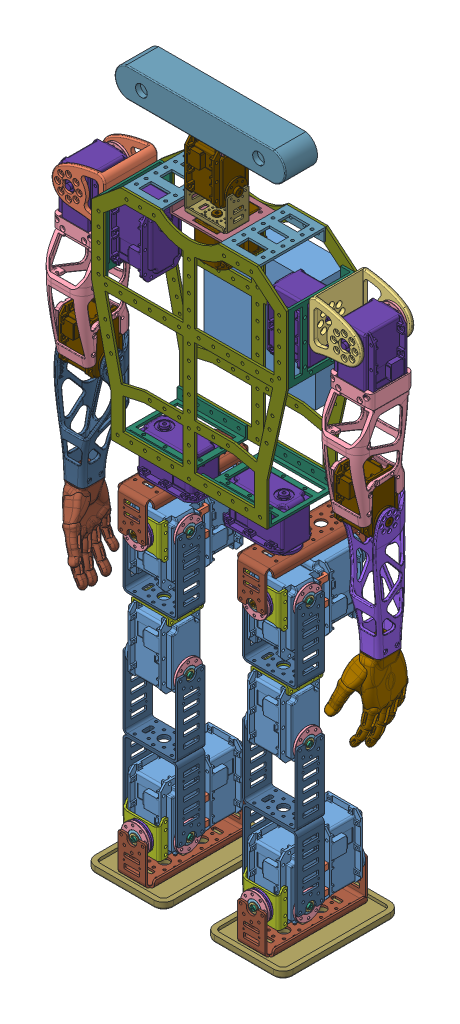
SolidWorks assembly main, configuration Default. Lengths in mm.
Overall size (334.21 729.22 145.63).
144 component instances, 32 part files, 59 mates.
Components (placement in the parent):
- leg_l2-1: leg_l2 [Default] at (32.287 -223.4121 -197.7719) x (0 0 1) z (-1 0 0) size (106.88 70.06 58.88)
  - MX-106T_step-1: MX-106T_step [Default] at origin size (40.2 65.92 55.3)
  - MX-106T_step-2: MX-106T_step [Default] at (-44 0 0) x (0 0 1) z (-1 0 0) size (40.2 65.92 55.3)
  - FR08-X101_2017-1: FR08-X101_2017 [Default] at (-27 -7 -17) x (0 -1 0) z (0 0 1) size (28 12.3 4.8)
  - FR08-X101_2017-2: FR08-X101_2017 [Default] at (-27 -7 17) x (0 1 0) z (0 0 -1) size (28 12.3 4.8)
  - RX64-CAP_2017-1: RX64-CAP_2017 [Default] at (0 0 -25.78) x (0.56381 0.825904 0) z (0 0 -1) size (9.5 9.5 2.2)
  - HN05-I101_2017-1: HN05-I101_2017 [Default] at (0 0 -26.02) x (0.824833 -0.565376 0) z (0.565376 0.824833 0) size (28 3.77 28)
  - MF128ZZ_2017-1: MF128ZZ_2017 [Default] at (0 0 -22.3) x (-0.923728 -0.383049 0) z (0.383049 -0.923728 0) size (14 3.48 14)
  - WB_M2.5X8_2017-1: WB_M2.5X8_2017 [Default] at (0 0 -28.08) x (0 0 1) z (0.825904 -0.56381 0) size (5.5 4.5 4.5)
  - FR05-S101_2017-1: FR05-S101_2017 [Default] at (24 0 0) x (0 1 0) z (0 0 1) size (36 9.31 38.02)
  - FR05-F101_2017-1: FR05-F101_2017 [Default] at (24 0 0) x (0 -0.707107 0.707107) z (1 0 0) size (27 27 5)
  - MF128ZZ_2017-2: MF128ZZ_2017 [Default] at (26.3 0 0) x (0 -1 0) z (0 0 1) size (14 3.48 14)
  - WB_M2.5X8_step-1: WB_M2.5X8_step [Default] at (32.08 0 0) x (-1 0 0) z (0 0.546944 0.837169) size (10.5 4.5 4.5)
  - HN05-I101_2017-2: HN05-I101_2017 [Default] at (30.02 0 0) x (0 -1 0) z (0 0 1) size (28 3.77 28)
  - RX64-CAP_2017-2: RX64-CAP_2017 [Default] at (29.78 0 0) x (0 0.837169 -0.546944) z (1 0 0) size (9.5 9.5 2.2)
- leg_l3-2: leg_l3 [Default] at (9.4719 -309.3189 -145.539) x (1 0 0) z (0 1 0) size (58.88 41.6 149.21)
  - HW-64106HXL_2017-1: HW-64106HXL_2017 [Default] at (-3.1848 38.233 13.9067) size (56 28 75)
  - FR05-S101_2017-1: FR05-S101_2017 [Default] at (22.8152 52.233 13.9067) x (0 -1 0) z (1 0 0) size (36 9.31 38.02)
  - MX-106T_step-1: MX-106T_step [Default] at (22.8152 52.233 -40.5933) x (0 1 0) z (-1 0 0) size (40.2 65.92 55.3)
  - HN05-I101_2017-1: HN05-I101_2017 [Default] at (48.8352 52.233 -40.5933) x (0 -0.637924 -0.7701) z (0 -0.7701 0.637924) size (28 3.77 28)
  - RX64-CAP_2017-1: RX64-CAP_2017 [Default] at (48.5952 52.233 -40.5933) x (0 0.837169 -0.546944) z (1 0 0) size (9.5 9.5 2.2)
  - MF128ZZ_2017-1: MF128ZZ_2017 [Default] at (45.1152 52.233 -40.5933) x (0 -0.162836 -0.986653) z (0 -0.986653 0.162836) size (14 3.48 14)
  - WB_M2.5X8_2017-1: WB_M2.5X8_2017 [Default] at (50.8952 52.233 -40.5933) x (-1 0 0) z (0 0.546944 0.837169) size (5.5 4.5 4.5)
- leg_l4-1: leg_l4 [Default] at (-9.8792 -490.5806 -151.7825) x (1 0 0) z (0 1 0) size (56 28 150)
  - HW-64106HXL_2017-1: HW-64106HXL_2017 [Default] at (16.1663 31.9894 68.6685) size (56 28 75)
  - HW-64106HXL_2017-2: HW-64106HXL_2017 [Default] at (68.1663 31.9894 68.6685) x (-1 0 0) z (0 0 -1) size (56 28 75)
- leg_l5-1: leg_l5 [Default] at (76.8682 -440.5941 -231.6442) x (0.699193 -0.033567 0.714144) z (-0.673395 -0.366444 0.642073) size (104.02 99.97 119.36)
  - MX-106T_step-1: MX-106T_step [Default] at (-5.1915 -29.4269 71.3073) x (-0.714144 -0.278818 -0.642073) z (-0.699193 0.240141 0.673395) size (40.2 65.92 55.3)
  - MX-106T_step-2: MX-106T_step [Default] at (-36.6138 -41.6949 43.056) x (0.699193 -0.240141 -0.673395) z (-0.714144 -0.278818 -0.642073) size (40.2 65.92 55.3)
  - FR08-X101_2017-1: FR08-X101_2017 [Default] at (-36.5946 -26.3638 62.8539) x (-0.033567 0.929835 -0.366444) z (0.699193 -0.240141 -0.673395) size (28 12.3 4.8)
  - FR08-X101_2017-2: FR08-X101_2017 [Default] at (-12.8221 -34.5286 39.9585) x (0.033567 -0.929835 0.366444) z (-0.699193 0.240141 0.673395) size (28 12.3 4.8)
  - HN05-I101_2017-1: HN05-I101_2017 [Default] at (13.0015 -35.6754 53.7855) x (0.048348 -0.923861 0.379661) z (0.713296 0.298014 0.634347) size (28 3.77 28)
  - RX64-CAP_2017-1: RX64-CAP_2017 [Default] at (12.8337 -35.6178 53.9472) x (-0.430608 0.610431 -0.664793) z (0.699193 -0.240141 -0.673395) size (9.5 9.5 2.2)
  - HN05-I101_2017-2: HN05-I101_2017 [Default] at (16.2471 -21.0568 90.5823) x (0.601193 -0.714144 -0.35856) z (-0.35856 -0.642073 0.677626) size (28 3.77 28)
  - RX64-CAP_2017-2: RX64-CAP_2017 [Default] at (16.0757 -21.1237 90.4282) x (-0.307188 0.949038 -0.070448) z (0.714144 0.278818 0.642073) size (9.5 9.5 2.2)
  - MF128ZZ_2017-1: MF128ZZ_2017 [Default] at (10.4005 -34.7821 56.2906) x (0.048348 -0.923861 0.379661) z (0.713296 0.298014 0.634347) size (14 3.48 14)
  - WB_M2.5X8_2017-1: WB_M2.5X8_2017 [Default] at (14.4419 -36.1701 52.3983) x (-0.699193 0.240141 0.673395) z (0.570706 0.754788 0.323403) size (5.5 4.5 4.5)
  - MF128ZZ_2017-2: MF128ZZ_2017 [Default] at (13.5905 -22.094 88.1938) x (0.601193 -0.714144 -0.35856) z (-0.35856 -0.642073 0.677626) size (14 3.48 14)
  - WB_M2.5X8_2017-2: WB_M2.5X8_2017 [Default] at (17.7183 -20.4824 91.905) x (-0.714144 -0.278818 -0.642073) z (-0.628994 -0.146927 0.763399) size (5.5 4.5 4.5)
  - FR05-S101_2017-1: FR05-S101_2017 [Default] at (11.948 -22.7353 86.717) x (0.033567 -0.929835 0.366444) z (0.699193 -0.240141 -0.673395) size (36 9.31 38.02)
  - FR05-F101_2017-1: FR05-F101_2017 [Default] at (11.948 -22.7353 86.717) x (0.699193 -0.240141 -0.673395) z (0.714144 0.278818 0.642073) size (27 27 5)
- leg_l6-1: leg_l6 [Default] at (81.6957 -592.3515 -172.7411) x (0 0 -1) z (0 1 0) size (120 80 44)
  - HW-64106HXW_2017-1: HW-64106HXW_2017 [Default] at (-3.9692 33.4087 61.4394) size (105 37.08 40)
  - foot_2017-1: foot_2017 [Default] at (44.5308 49.4087 57.4394) x (-1 0 0) z (0 1 0) size (120 7 80)
- HW-64106HXW_2017-3: HW-64106HXW_2017 [Default] at (170.787 -186.4121 -265.7719) x (0 0 1) z (0 -1 0) size (105 37.08 40)
- leg_l2-2: leg_l2 [Default] at (154.787 -223.4121 -197.7719) x (0 0 1) z (-1 0 0) size (106.88 70.06 58.88)
  - MX-106T_step-1: MX-106T_step [Default] at origin size (40.2 65.92 55.3)
  - MX-106T_step-2: MX-106T_step [Default] at (-44 0 0) x (0 0 1) z (-1 0 0) size (40.2 65.92 55.3)
  - FR08-X101_2017-1: FR08-X101_2017 [Default] at (-27 -7 -17) x (0 -1 0) z (0 0 1) size (28 12.3 4.8)
  - FR08-X101_2017-2: FR08-X101_2017 [Default] at (-27 -7 17) x (0 1 0) z (0 0 -1) size (28 12.3 4.8)
  - RX64-CAP_2017-1: RX64-CAP_2017 [Default] at (0 0 -25.78) x (0.56381 0.825904 0) z (0 0 -1) size (9.5 9.5 2.2)
  - HN05-I101_2017-1: HN05-I101_2017 [Default] at (0 0 -26.02) x (0.824833 -0.565376 0) z (0.565376 0.824833 0) size (28 3.77 28)
  - MF128ZZ_2017-1: MF128ZZ_2017 [Default] at (0 0 -22.3) x (-0.923728 -0.383049 0) z (0.383049 -0.923728 0) size (14 3.48 14)
  - WB_M2.5X8_2017-1: WB_M2.5X8_2017 [Default] at (0 0 -28.08) x (0 0 1) z (0.825904 -0.56381 0) size (5.5 4.5 4.5)
  - FR05-S101_2017-1: FR05-S101_2017 [Default] at (24 0 0) x (0 1 0) z (0 0 1) size (36 9.31 38.02)
  - FR05-F101_2017-1: FR05-F101_2017 [Default] at (24 0 0) x (0 -0.707107 0.707107) z (1 0 0) size (27 27 5)
  - MF128ZZ_2017-2: MF128ZZ_2017 [Default] at (26.3 0 0) x (0 -1 0) z (0 0 1) size (14 3.48 14)
  - WB_M2.5X8_step-1: WB_M2.5X8_step [Default] at (32.08 0 0) x (-1 0 0) z (0 0.546944 0.837169) size (10.5 4.5 4.5)
  - HN05-I101_2017-2: HN05-I101_2017 [Default] at (30.02 0 0) x (0 -1 0) z (0 0 1) size (28 3.77 28)
  - RX64-CAP_2017-2: RX64-CAP_2017 [Default] at (29.78 0 0) x (0 0.837169 -0.546944) z (1 0 0) size (9.5 9.5 2.2)
- leg_l3-3: leg_l3 [Default] at (131.9719 -309.3189 -145.539) x (1 0 0) z (0 1 0) size (58.88 41.6 149.21)
  - HW-64106HXL_2017-1: HW-64106HXL_2017 [Default] at (-3.1848 38.233 13.9067) size (56 28 75)
  - FR05-S101_2017-1: FR05-S101_2017 [Default] at (22.8152 52.233 13.9067) x (0 -1 0) z (1 0 0) size (36 9.31 38.02)
  - MX-106T_step-1: MX-106T_step [Default] at (22.8152 52.233 -40.5933) x (0 1 0) z (-1 0 0) size (40.2 65.92 55.3)
  - HN05-I101_2017-1: HN05-I101_2017 [Default] at (48.8352 52.233 -40.5933) x (0 -0.637924 -0.7701) z (0 -0.7701 0.637924) size (28 3.77 28)
  - RX64-CAP_2017-1: RX64-CAP_2017 [Default] at (48.5952 52.233 -40.5933) x (0 0.837169 -0.546944) z (1 0 0) size (9.5 9.5 2.2)
  - MF128ZZ_2017-1: MF128ZZ_2017 [Default] at (45.1152 52.233 -40.5933) x (0 -0.162836 -0.986653) z (0 -0.986653 0.162836) size (14 3.48 14)
  - WB_M2.5X8_2017-1: WB_M2.5X8_2017 [Default] at (50.8952 52.233 -40.5933) x (-1 0 0) z (0 0.546944 0.837169) size (5.5 4.5 4.5)
- leg_l4-2: leg_l4 [Default] at (112.6208 -490.5806 -151.7825) x (1 0 0) z (0 1 0) size (56 28 150)
  - HW-64106HXL_2017-1: HW-64106HXL_2017 [Default] at (16.1663 31.9894 68.6685) size (56 28 75)
  - HW-64106HXL_2017-2: HW-64106HXL_2017 [Default] at (68.1663 31.9894 68.6685) x (-1 0 0) z (0 0 -1) size (56 28 75)
- leg_l5-2: leg_l5 [Default] at (199.3682 -440.5941 -231.6442) x (0.699193 -0.033567 0.714144) z (-0.673395 -0.366444 0.642073) size (104.02 99.97 119.36)
  - MX-106T_step-1: MX-106T_step [Default] at (-5.1915 -29.4269 71.3073) x (-0.714144 -0.278818 -0.642073) z (-0.699193 0.240141 0.673395) size (40.2 65.92 55.3)
  - MX-106T_step-2: MX-106T_step [Default] at (-36.6138 -41.6949 43.056) x (0.699193 -0.240141 -0.673395) z (-0.714144 -0.278818 -0.642073) size (40.2 65.92 55.3)
  - FR08-X101_2017-1: FR08-X101_2017 [Default] at (-36.5946 -26.3638 62.8539) x (-0.033567 0.929835 -0.366444) z (0.699193 -0.240141 -0.673395) size (28 12.3 4.8)
  - FR08-X101_2017-2: FR08-X101_2017 [Default] at (-12.8221 -34.5286 39.9585) x (0.033567 -0.929835 0.366444) z (-0.699193 0.240141 0.673395) size (28 12.3 4.8)
  - HN05-I101_2017-1: HN05-I101_2017 [Default] at (13.0015 -35.6754 53.7855) x (0.048348 -0.923861 0.379661) z (0.713296 0.298014 0.634347) size (28 3.77 28)
  - RX64-CAP_2017-1: RX64-CAP_2017 [Default] at (12.8337 -35.6178 53.9472) x (-0.430608 0.610431 -0.664793) z (0.699193 -0.240141 -0.673395) size (9.5 9.5 2.2)
  - HN05-I101_2017-2: HN05-I101_2017 [Default] at (16.2471 -21.0568 90.5823) x (0.601193 -0.714144 -0.35856) z (-0.35856 -0.642073 0.677626) size (28 3.77 28)
  - RX64-CAP_2017-2: RX64-CAP_2017 [Default] at (16.0757 -21.1237 90.4282) x (-0.307188 0.949038 -0.070448) z (0.714144 0.278818 0.642073) size (9.5 9.5 2.2)
  - MF128ZZ_2017-1: MF128ZZ_2017 [Default] at (10.4005 -34.7821 56.2906) x (0.048348 -0.923861 0.379661) z (0.713296 0.298014 0.634347) size (14 3.48 14)
  - WB_M2.5X8_2017-1: WB_M2.5X8_2017 [Default] at (14.4419 -36.1701 52.3983) x (-0.699193 0.240141 0.673395) z (0.570706 0.754788 0.323403) size (5.5 4.5 4.5)
  - MF128ZZ_2017-2: MF128ZZ_2017 [Default] at (13.5905 -22.094 88.1938) x (0.601193 -0.714144 -0.35856) z (-0.35856 -0.642073 0.677626) size (14 3.48 14)
  - WB_M2.5X8_2017-2: WB_M2.5X8_2017 [Default] at (17.7183 -20.4824 91.905) x (-0.714144 -0.278818 -0.642073) z (-0.628994 -0.146927 0.763399) size (5.5 4.5 4.5)
  - FR05-S101_2017-1: FR05-S101_2017 [Default] at (11.948 -22.7353 86.717) x (0.033567 -0.929835 0.366444) z (0.699193 -0.240141 -0.673395) size (36 9.31 38.02)
  - FR05-F101_2017-1: FR05-F101_2017 [Default] at (11.948 -22.7353 86.717) x (0.699193 -0.240141 -0.673395) z (0.714144 0.278818 0.642073) size (27 27 5)
- leg_l6-2: leg_l6 [Default] at (204.1957 -592.3515 -172.7411) x (0 0 -1) z (0 1 0) size (120 80 44)
  - HW-64106HXW_2017-1: HW-64106HXW_2017 [Default] at (-3.9692 33.4087 61.4394) size (105 37.08 40)
  - foot_2017-1: foot_2017 [Default] at (44.5308 49.4087 57.4394) x (-1 0 0) z (0 1 0) size (120 7 80)
- HW-64106HXW_2017-5: HW-64106HXW_2017 [Default] at (48.287 -186.4121 -265.7719) x (0 0 1) z (0 -1 0) size (105 37.08 40)
- torso-1: torso [Default] at (93.537 76.1289 -198.2719) size (217.43 273.5 112.95)
  - torso_frame_head-1: torso_frame_head [Default] at (0 -3.827 -35) size (76 8 58.5)
  - torso_frame_link-1: torso_frame_link [Default] at (-50 -6.241 0) x (0 0 1) z (-1 0 0) size (75.11 12.7 53.47)
  - torso_frame_motor-1: torso_frame_motor [Default] at (-98.857 -88.541 0) x (0 0 1) z (-1 0 0) size (68 70 36.25)
  - torso_main-1: torso_main [Default] at (0 0 34) size (200 228.5 2.29)
  - torso_main-2: torso_main [Default] at (0 0 -36.286) size (200 228.5 2.29)
  - torso_frame_link-2: torso_frame_link [Default] at (50 -6.241 0) x (0 0 1) z (-1 0 0) size (75.11 12.7 53.47)
  - torso_frame_motor-2: torso_frame_motor [Default] at (98.857 -88.541 0) x (0 0 -1) z (1 0 0) size (68 70 36.25)
  - torso_frame_motor-3: torso_frame_motor [Default] at (10 -220.898 0) x (0 0 -1) z (0 -1 0) size (68 70 36.25)
  - torso_frame_motor-4: torso_frame_motor [Default] at (-10 -220.898 0) x (0 0 1) z (0 -1 0) size (68 70 36.25)
  - MX-64T_step-1: MX-64T_step [Default] at (80.714 -37.291 0) x (0 0 -1) z (1 0 0) size (40.2 62.1 50)
  - MX-64T_step-2: MX-64T_step [Default] at (-80.714 -37.291 0) x (0 0 1) z (-1 0 0) size (40.2 62.1 50)
  - MX-64T_step-3: MX-64T_step [Default] at (61.25 -239.041 0) x (0 0 -1) z (0 -1 0) size (40.2 62.1 50)
  - MX-64T_step-4: MX-64T_step [Default] at (-61.25 -239.041 0) x (0 0 1) z (0 -1 0) size (40.2 62.1 50)
  - MX28_step-1: MX28_step [Default] at (11.9078 -61.4181 -29.7938) x (-1 0 0) z (0 1 0) size (35.6 50.71 42.6)
  - nuc-1: nuc [Default] at (0 -108.0269 -54.066) size (114.3 111.76 35.56)
- arm_shoulder_right-1: arm_shoulder_right [MX-28_Right] at (-41.4573 39.516 -207.4216) size (56.51 54.5 59.55)
- arm_shoulder_left-1: arm_shoulder_left [MX-28_Right] at (228.5313 39.516 -207.4216) size (56.51 54.5 59.55)
- arm_l2-1: arm_l2 [Default] at (-59.4585 -11.9064 -257.1398) size (45.99 187.91 62.65)
  - MX-64T_step-1: MX-64T_step [Default] at (11.6566 50.7443 49.8736) size (40.2 62.1 50)
  - HN05-I101_2017-1: HN05-I101_2017 [Default] at (11.6566 50.7443 26.3536) x (-0.978167 -0.207821 0) z (0.207821 -0.978167 0) size (28 3.77 28)
  - MF128ZZ_2017-1: MF128ZZ_2017 [Default] at (11.6566 50.7443 30.0736) x (-0.981893 -0.189437 0) z (0.189437 -0.981893 0) size (14 3.48 14)
  - RX64-CAP_2017-1: RX64-CAP_2017 [Default] at (11.6566 50.7443 26.5936) x (-0.772804 -0.634645 0) z (0 0 -1) size (9.5 9.5 2.2)
  - WB_M2.5X8_2017-1: WB_M2.5X8_2017 [Default] at (11.6566 50.7443 24.2936) x (0 0 1) z (-0.923728 -0.383049 0) size (5.5 4.5 4.5)
  - arm_upperarm-1: arm_upperarm [Default] at (-19.8184 -15.6443 22.4331) size (44.79 120.44 61.97)
  - MX28_step-1: MX28_step [Default] at (-30.9345 -67.7118 42.6951) x (0 0 1) z (1 0 0) size (35.6 50.71 42.6)
  - MX28_HN07-i101-1: MX28_HN07-i101 [Default] at (-8.5434 -105.0057 54.6029) x (0 0.707328 0.706886) z (0 -0.706886 0.707328) size (22 3.05 22)
  - MF106ZZ-1: MF106ZZ [Défaut] at (-8.3934 -105.0057 54.6029) x (0 -0.837169 -0.546944) z (0 -0.546944 0.837169) size (11.2 3 11.2)
  - RX28-CAP-1: RX28-CAP [Défaut] at (-8.3934 -105.0057 54.6029) x (0 0.357314 -0.933984) z (-1 0 0) size (7.2 7.2 1.8)
- arm_l2-2: arm_l2 [Default] at (223.2193 -11.9064 -257.0362) size (45.99 187.91 62.65)
  - MX-64T_step-1: MX-64T_step [Default] at (11.6566 50.7443 49.8736) size (40.2 62.1 50)
  - HN05-I101_2017-1: HN05-I101_2017 [Default] at (11.6566 50.7443 26.3536) x (-0.978167 -0.207821 0) z (0.207821 -0.978167 0) size (28 3.77 28)
  - MF128ZZ_2017-1: MF128ZZ_2017 [Default] at (11.6566 50.7443 30.0736) x (-0.981893 -0.189437 0) z (0.189437 -0.981893 0) size (14 3.48 14)
  - RX64-CAP_2017-1: RX64-CAP_2017 [Default] at (11.6566 50.7443 26.5936) x (-0.772804 -0.634645 0) z (0 0 -1) size (9.5 9.5 2.2)
  - WB_M2.5X8_2017-1: WB_M2.5X8_2017 [Default] at (11.6566 50.7443 24.2936) x (0 0 1) z (-0.923728 -0.383049 0) size (5.5 4.5 4.5)
  - arm_upperarm-1: arm_upperarm [Default] at (-19.8184 -15.6443 22.4331) size (44.79 120.44 61.97)
  - MX28_step-1: MX28_step [Default] at (-30.9345 -67.7118 42.6951) x (0 0 1) z (1 0 0) size (35.6 50.71 42.6)
  - MX28_HN07-i101-1: MX28_HN07-i101 [Default] at (-8.5434 -105.0057 54.6029) x (0 0.707328 0.706886) z (0 -0.706886 0.707328) size (22 3.05 22)
  - MF106ZZ-1: MF106ZZ [Défaut] at (-8.3934 -105.0057 54.6029) x (0 -0.837169 -0.546944) z (0 -0.546944 0.837169) size (11.2 3 11.2)
  - RX28-CAP-1: RX28-CAP [Défaut] at (-8.3934 -105.0057 54.6029) x (0 0.357314 -0.933984) z (-1 0 0) size (7.2 7.2 1.8)
- arm_l3-1: arm_l3 [Default] at (204.6652 -273.2178 -305.5465) size (55.2 228.71 65.03)
  - arm_forearm_left-2: arm_forearm_left [MX-28-right] at (51.4657 156.3057 103.1131) size (55.2 137.66 53.14)
  - arm_hand_left-1: arm_hand_left [left_fake_human_like_hand] at (40.8108 36.3057 99.1131) x (0 0 -1) z (0 -1 0) size (64.5 37.73 100.68)
- arm_r3-1: arm_r3 [Default] at (-61.115 -260.9793 -320.9419) size (55.2 228.71 65.03)
  - arm_forearm_right-1: arm_forearm_right [MX-28-right] at (13.5631 144.0672 118.4049) size (55.2 137.66 53.14)
  - arm_hand_right-1: arm_hand_right [left_fake_human_like_hand] at (3.2131 24.0672 114.4049) x (0 0 -1) z (0 -1 0) size (59.65 36.84 100.68)
- FR07-H101K-1: FR07-H101K [Default] at (93.537 78.0519 -190.7719) x (-1 0 0) z (0 1 0) size (44 26 32.5)
- head_2-1: head_2 [Default] at (77.6258 211.8282 -253.1181) size (175 84.64 38.65)
  - MX28_step-1: MX28_step [Default] at (-26.9298 -63.9825 50.4384) x (0 0 1) z (1 0 0) size (35.6 50.71 42.6)
  - MX28_HN07-i101-1: MX28_HN07-i101 [Default] at (-4.5387 -101.2764 62.3462) x (0 0.153917 -0.988084) z (0 0.988084 0.153917) size (22 3.05 22)
  - MF106ZZ-1: MF106ZZ [Défaut] at (-4.3887 -101.2764 62.3462) x (0 0.577041 0.816715) z (0 0.816715 -0.577041) size (11.2 3 11.2)
  - RX28-CAP-1: RX28-CAP [Défaut] at (-4.3887 -101.2764 62.3462) x (0 1 0) z (-1 0 0) size (7.2 7.2 1.8)
  - FR07-S101K-1: FR07-S101K [Default] at (15.6613 -60.4964 62.0962) x (-1 0 0) z (0 1 0) size (33 27.5 8.5)
  - ZED-Body-1: ZED-Body [Default] at (15.6613 -44.1964 46.4962) size (175 30 38)
Mates (geometry in assembly coordinates):
- Concentric3: concentric anti-aligned: cylinder of leg_l2-1/HN05-I101_2017-1 through (58.307 -223.4121 -197.7719) axis (-1 0 0) radius 14; cylinder of leg_l3-2/HW-64106HXL_2017-1 through (60.287 -223.4121 -197.7719) axis (1 0 0) radius 5.1
- Concentric4: concentric anti-aligned: cylinder of leg_l3-2/HN05-I101_2017-1 through (58.307 -349.9121 -197.7719) axis (-1 0 0) radius 14; cylinder of leg_l4-1/HW-64106HXL_2017-1 through (60.287 -349.9121 -197.7719) axis (1 0 0) radius 5.1
- Concentric5: concentric anti-aligned: cylinder of leg_l4-1/HW-64106HXL_2017-2 through (4.287 -493.9121 -197.7719) axis (-1 0 0) radius 5.1; cylinder of leg_l5-1/MX-106T_step-1 through (1.097 -493.9121 -197.7719) axis (1 0 0) radius 5
- Coincident5: coincident anti-aligned: plane of leg_l4-1/HW-64106HXL_2017-2 through (6.287 -493.9121 -197.7719) normal (1 0 0); plane of leg_l5-1/MX-106T_step-1 through (6.287 -493.9121 -197.7719) normal (-1 0 0)
- Coincident6: coincident anti-aligned: plane of leg_l2-1/MX-106T_step-1 through (6.287 -223.4121 -197.7719) normal (-1 0 0); plane of leg_l3-2/HW-64106HXL_2017-1 through (6.287 -223.4121 -197.7719) normal (1 0 0)
- Coincident7: coincident anti-aligned: plane of leg_l2-1/MX-106T_step-1 through (6.287 -223.4121 -197.7719) normal (-1 0 0); plane of leg_l3-2/HW-64106HXL_2017-1 through (6.287 -223.4121 -197.7719) normal (1 0 0)
- Coincident8: coincident anti-aligned: plane of leg_l3-2/MX-106T_step-1 through (6.287 -349.9121 -197.7719) normal (-1 0 0); plane of leg_l4-1/HW-64106HXL_2017-1 through (6.287 -349.9121 -197.7719) normal (1 0 0)
- Concentric6: concentric anti-aligned: cylinder of leg_l5-1/MX-106T_step-2 through (32.287 -493.9121 -272.9619) axis (0 0 1) radius 14; cylinder of leg_l6-1/HW-64106HXW_2017-1 through (32.287 -493.9121 -269.7719) axis (0 0 -1) radius 5.1
- Coincident9: coincident anti-aligned: plane of leg_l5-1/MX-106T_step-2 through (32.287 -493.9121 -267.7719) normal (0 0 -1); plane of leg_l6-1/HW-64106HXW_2017-1 through (32.287 -508.8282 -267.7719) normal (0 0 1)
- Concentric8: concentric aligned: cylinder of HW-64106HXW_2017-3 through (154.787 -223.4121 -164.7719) axis (0 0 1) radius 5.1; cylinder of leg_l2-2/MX-106T_step-2 through (154.787 -223.4121 -272.9619) axis (0 0 1) radius 5
- Coincident11: coincident anti-aligned: plane of HW-64106HXW_2017-3 through (154.787 -208.4961 -267.7719) normal (0 0 1); plane of leg_l2-2/MX-106T_step-2 through (154.787 -223.4121 -267.7719) normal (0 0 -1)
- Concentric9: concentric aligned: cylinder of leg_l2-2/MX-106T_step-1 through (123.597 -223.4121 -197.7719) axis (1 0 0) radius 5; cylinder of leg_l3-3/HW-64106HXL_2017-1 through (128.787 -223.4121 -197.7719) axis (1 0 0) radius 5.1
- Coincident12: coincident anti-aligned: plane of leg_l2-2/MX-106T_step-1 through (128.787 -223.4121 -197.7719) normal (-1 0 0); plane of leg_l3-3/HW-64106HXL_2017-1 through (128.787 -223.4121 -197.7719) normal (1 0 0)
- Concentric10: concentric aligned: cylinder of leg_l3-3/MX-106T_step-1 through (123.597 -349.9121 -197.7719) axis (1 0 0) radius 5; cylinder of leg_l4-2/HW-64106HXL_2017-1 through (128.787 -349.9121 -197.7719) axis (1 0 0) radius 5.1
- Coincident13: coincident anti-aligned: plane of leg_l3-3/MX-106T_step-1 through (128.787 -349.9121 -197.7719) normal (-1 0 0); plane of leg_l4-2/HW-64106HXL_2017-1 through (128.787 -349.9121 -197.7719) normal (1 0 0)
- Concentric13: concentric anti-aligned: cylinder of leg_l4-2/HW-64106HXL_2017-2 through (126.787 -493.9121 -197.7719) axis (-1 0 0) radius 5.1; cylinder of leg_l5-2/MX-106T_step-1 through (123.597 -493.9121 -197.7719) axis (1 0 0) radius 5
- Coincident16: coincident anti-aligned: plane of leg_l4-2/HW-64106HXL_2017-2 through (128.787 -493.9121 -197.7719) normal (1 0 0); plane of leg_l5-2/MX-106T_step-1 through (128.787 -493.9121 -197.7719) normal (-1 0 0)
- Parallel3: parallel anti-aligned: plane of leg_l2-1/MX-106T_step-1 through (32.287 -223.4121 -197.7719) normal (0 0 1); plane of leg_l3-2/HW-64106HXL_2017-1 through (6.287 -295.4121 -183.7719) normal (0 0 -1)
- Parallel4: parallel aligned: plane of leg_l3-2/MX-106T_step-1 through (32.287 -349.9121 -197.7719) normal (0 0 -1); plane of leg_l4-1/HW-64106HXL_2017-1 through (6.287 -421.9121 -183.7719) normal (0 0 -1)
- Parallel5: parallel aligned: plane of leg_l4-1/HW-64106HXL_2017-2 through (58.287 -421.9121 -183.7719) normal (0 0 -1); plane of leg_l5-1/MX-106T_step-1 through (32.287 -493.9121 -197.7719) normal (0 0 -1)
- Parallel6: parallel aligned: plane of leg_l5-1/MX-106T_step-1 through (32.287 -493.9121 -197.7719) normal (-1 0 0); plane of leg_l6-1/HW-64106HXW_2017-1 through (48.287 -530.9121 -168.7719) normal (-1 0 0)
- Parallel8: parallel aligned: plane of HW-64106HXW_2017-3 through (170.787 -186.4121 -265.7719) normal (-1 0 0); plane of leg_l2-2/MX-106T_step-1 through (154.787 -223.4121 -197.7719) normal (-1 0 0)
- Parallel9: parallel anti-aligned: plane of leg_l2-2/MX-106T_step-1 through (154.787 -223.4121 -197.7719) normal (0 0 1); plane of leg_l3-3/HW-64106HXL_2017-1 through (128.787 -295.4121 -183.7719) normal (0 0 -1)
- Parallel10: parallel aligned: plane of leg_l3-3/MX-106T_step-1 through (154.787 -349.9121 -197.7719) normal (0 0 -1); plane of leg_l4-2/HW-64106HXL_2017-1 through (128.787 -421.9121 -183.7719) normal (0 0 -1)
- Parallel11: parallel aligned: plane of leg_l4-2/HW-64106HXL_2017-2 through (180.787 -421.9121 -183.7719) normal (0 0 -1); plane of leg_l5-2/MX-106T_step-1 through (154.787 -493.9121 -197.7719) normal (0 0 -1)
- Concentric19: concentric aligned: cylinder of leg_l2-1/MX-106T_step-2 through (32.287 -223.4121 -272.9619) axis (0 0 1) radius 5; cylinder of HW-64106HXW_2017-5 through (32.287 -223.4121 -164.7719) axis (0 0 1) radius 5.1
- Coincident39: coincident anti-aligned: plane of leg_l2-1/MX-106T_step-2 through (32.287 -223.4121 -267.7719) normal (0 0 -1); plane of HW-64106HXW_2017-5 through (32.287 -208.4961 -267.7719) normal (0 0 1)
- Parallel18: parallel aligned: plane of leg_l2-1/MX-106T_step-1 through (32.287 -223.4121 -197.7719) normal (-1 0 0); plane of HW-64106HXW_2017-5 through (48.287 -186.4121 -265.7719) normal (-1 0 0)
- Concentric20: concentric anti-aligned: cylinder of leg_l5-2/MX-106T_step-2 through (154.787 -493.9121 -272.9619) axis (0 0 1) radius 5; cylinder of leg_l6-2/HW-64106HXW_2017-1 through (154.787 -493.9121 -269.7719) axis (0 0 -1) radius 5.1
- Coincident42: coincident anti-aligned: plane of leg_l5-2/MX-106T_step-2 through (154.787 -493.9121 -267.7719) normal (0 0 -1); plane of leg_l6-2/HW-64106HXW_2017-1 through (154.787 -508.8282 -267.7719) normal (0 0 1)
- Parallel19: parallel aligned: plane of leg_l5-2/MX-106T_step-1 through (154.787 -493.9121 -197.7719) normal (-1 0 0); plane of leg_l6-2/HW-64106HXW_2017-1 through (170.787 -530.9121 -168.7719) normal (-1 0 0)
- Concentric21: concentric anti-aligned: cylinder of HW-64106HXW_2017-5 through (32.287 -304.7334 -198.2719) axis (0 -1 0) radius 5.1; cylinder of torso-1/MX-64T_step-4 through (32.287 -191.2871 -198.2719) axis (0 1 0) radius 5
- Coincident43: coincident anti-aligned: plane of HW-64106HXW_2017-5 through (32.287 -186.4121 -192.0219) normal (0 1 0); plane of torso-1/MX-64T_step-4 through (32.287 -186.4121 -198.2719) normal (0 -1 0)
- Concentric22: concentric anti-aligned: cylinder of HW-64106HXW_2017-3 through (154.787 -304.7334 -198.2719) axis (0 -1 0) radius 5.1; cylinder of torso-1/MX-64T_step-3 through (154.787 -191.2871 -198.2719) axis (0 1 0) radius 2.75
- Coincident44: coincident anti-aligned: plane of HW-64106HXW_2017-3 through (154.787 -186.4121 -192.0219) normal (0 1 0); plane of torso-1/MX-64T_step-3 through (154.787 -186.4121 -198.2719) normal (0 -1 0)
- Concentric23: concentric aligned: cylinder of torso-1/MX-64T_step-2 through (-15.552 38.8379 -198.2719) axis (1 0 0) radius 14; cylinder of arm_shoulder_right-1 through (-65.2657 38.8379 -198.2719) axis (1 0 0) radius 5.8437
- Coincident45: coincident anti-aligned: plane of torso-1/MX-64T_step-2 through (-10.677 38.8379 -198.2719) normal (-1 0 0); plane of arm_shoulder_right-1 through (-10.677 14.0879 -234.5375) normal (1 0 0)
- Concentric24: concentric aligned: cylinder of torso-1/MX-64T_step-1 through (202.626 38.8379 -198.2719) axis (-1 0 0) radius 5; cylinder of arm_shoulder_left-1 through (252.3398 38.8379 -198.2719) axis (-1 0 0) radius 5.8437
- Coincident46: coincident anti-aligned: plane of torso-1/MX-64T_step-1 through (197.751 38.8379 -198.2719) normal (1 0 0); plane of arm_shoulder_left-1 through (197.751 14.0879 -234.5375) normal (-1 0 0)
- Concentric25: concentric aligned: cylinder of arm_shoulder_right-1 through (-47.8019 38.8379 -234.5375) axis (0 0 1) radius 5.8437; cylinder of arm_l2-1/HN05-I101_2017-1 through (-47.8019 38.8379 -230.7862) axis (0 0 1) radius 14
- Coincident47: coincident anti-aligned: plane of arm_shoulder_right-1 through (-32.0359 19.8146 -230.7562) normal (0 0 1); plane of arm_l2-1/HN05-I101_2017-1 through (-76.3429 48.0664 -230.7562) normal (0 0 -1)
- Concentric26: concentric anti-aligned: cylinder of arm_shoulder_left-1 through (234.876 38.8379 -234.5375) axis (0 0 1) radius 5.8437; cylinder of arm_l2-2/MX-64T_step-1 through (234.876 38.8379 -178.7876) axis (0 0 -1) radius 14
- Coincident48: coincident anti-aligned: plane of arm_shoulder_left-1 through (219.11 19.8146 -183.6626) normal (0 0 -1); plane of arm_l2-2/MX-64T_step-1 through (234.876 38.8379 -183.6626) normal (0 0 1)
- Concentric27: concentric anti-aligned: cylinder of arm_l2-2/MX28_step-1 through (258.7685 -116.9121 -202.4333) axis (-1 0 0) radius 4; cylinder of arm_l3-1/arm_forearm_left-2 through (207.9968 -116.9121 -202.4333) axis (1 0 0) radius 4.1
- Coincident49: coincident anti-aligned: plane of arm_l2-2/MX28_step-1 through (255.626 -116.9121 -202.4333) normal (1 0 0); plane of arm_l3-1/arm_forearm_left-2 through (255.626 -116.9121 -202.4333) normal (-1 0 0)
- Concentric28: concentric anti-aligned: cylinder of arm_l2-1/MX28_HN07-i101-1 through (-68.1544 -116.9121 -202.537) axis (1 0 0) radius 11; cylinder of arm_r3-1/arm_forearm_right-1 through (-20.4227 -116.9121 -202.537) axis (-1 0 0) radius 4.1
- Coincident50: coincident anti-aligned: plane of arm_l2-1/MX28_step-1 through (-27.0519 -116.9121 -202.537) normal (1 0 0); plane of arm_r3-1/arm_forearm_right-1 through (-27.0519 -116.9121 -202.537) normal (-1 0 0)
- Concentric29: concentric aligned: cylinder of torso-1/MX28_step-1 through (93.537 81.1944 -190.7719) axis (0 -1 0) radius 4; cylinder of FR07-H101K-1 through (93.537 79.5519 -190.7719) axis (0 -1 0) radius 4
- Coincident52: coincident anti-aligned: plane of torso-1/MX28_step-1 through (93.537 78.0519 -190.7719) normal (0 1 0); plane of FR07-H101K-1 through (93.537 78.0519 -190.7719) normal (0 -1 0)
- Concentric30: concentric aligned: cylinder of FR07-H101K-1 through (115.537 110.5519 -190.7719) axis (-1 0 0) radius 4; cylinder of head_2-1/MX28_step-1 through (117.1795 110.5519 -190.7719) axis (-1 0 0) radius 11
- Coincident53: coincident anti-aligned: plane of FR07-H101K-1 through (114.037 110.5519 -190.7719) normal (-1 0 0); plane of head_2-1/MX28_step-1 through (114.037 110.5519 -190.7719) normal (1 0 0)
- Parallel20: parallel aligned: plane of arm_shoulder_right-1 through (-16.177 14.0879 -234.5375) normal (-1 0 0); plane of arm_l2-1/MX-64T_step-1 through (-62.3019 51.8379 -227.7662) normal (-1 0 0)
- Parallel21: parallel aligned: plane of torso-1/torso_main-1 through (93.537 116.1289 -161.9859) normal (0 0 1); plane of arm_shoulder_right-1 through (-32.0359 19.8146 -179.8813) normal (0 0 1)
- Parallel22: parallel aligned: plane of torso-1/torso_main-1 through (93.537 116.1289 -161.9859) normal (0 0 1); plane of arm_shoulder_left-1 through (219.11 19.8146 -179.8813) normal (0 0 1)
- Parallel23: parallel aligned: plane of arm_shoulder_left-1 through (203.251 14.0879 -234.5375) normal (1 0 0); plane of arm_l2-2/MX-64T_step-1 through (249.376 -3.6621 -227.6626) normal (1 0 0)
- Parallel24: parallel: plane of arm_l2-2/MX28_step-1 through (217.126 -83.9121 -190.2333) normal (0 0 1); line of arm_l3-1/arm_forearm_left-2 through (258.626 -132.4346 -213.2367) axis (0 1 0)
- Parallel25: parallel: plane of arm_l2-1/MX28_step-1 through (-65.5519 -128.9121 -214.737) normal (0 0 -1); line of arm_r3-1/arm_forearm_right-1 through (-70.8977 -113.5973 -214.2896) axis (0 -1 0)
- Parallel26: parallel aligned: plane of torso-1/torso_main-1 through (93.537 116.1289 -161.9859) normal (0 0 1); plane of FR07-H101K-1 through (73.037 78.0519 -179.7719) normal (0 0 1)
- Parallel27: parallel aligned: plane of FR07-H101K-1 through (73.037 78.0519 -179.7719) normal (0 0 1); plane of head_2-1/MX28_step-1 through (80.287 143.1519 -172.9719) normal (0 0 1)
